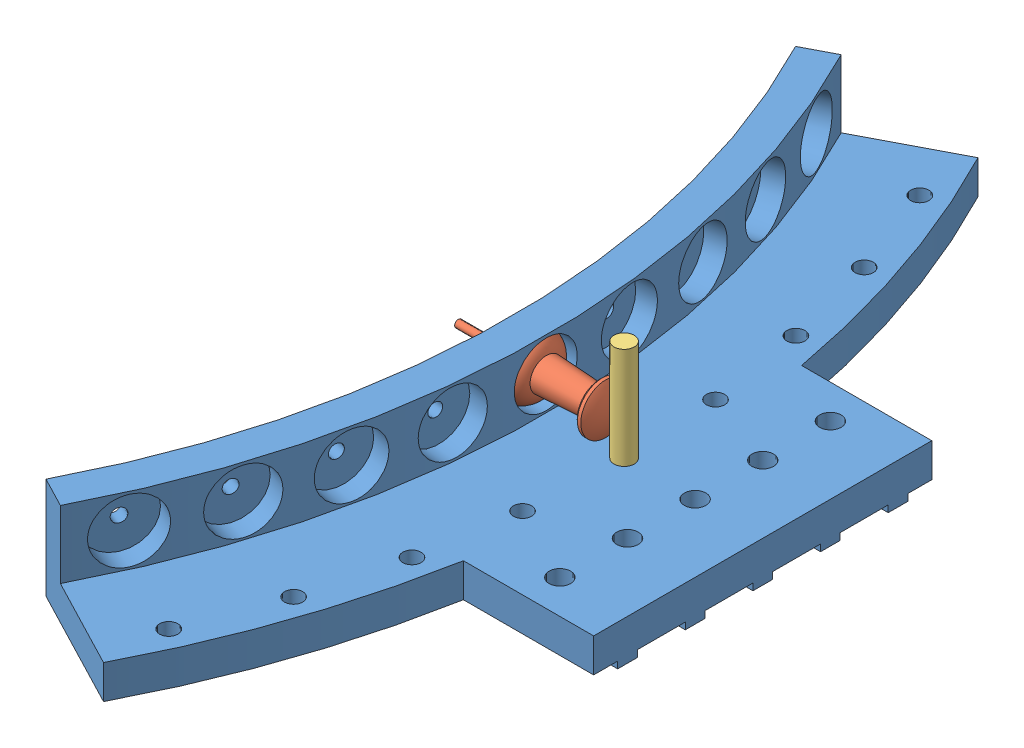
SolidWorks assembly ThumbtackWithSupport, configuration Default. Lengths in mm.
Overall size (50.56 21 129.29).
3 component instances, 3 part files, 4 mates.
Components (placement in the parent):
- ThumbtackSupport-1: ThumbtackSupport [Default] at (-94.9939 63.0635 100.913) size (50.56 16 129.29)
- Thumbtack-1: Thumbtack [Default] at (27.0061 73.0635 100.913) x (0 0 -1) z (1 0 0) size (9.3 9.3 22.8)
- Screw3mm-1: Screw3mm [Default] at (41.5061 83.0635 100.913) x (1 0 0) z (0 -1 0) size (3 3 20)
Mates (geometry in assembly coordinates):
- Coincident1: coincident anti-aligned: plane of ThumbtackSupport-1 through (27.0061 73.0635 100.913) normal (1 0 0); plane of Thumbtack-1 through (27.0061 73.6135 100.913) normal (-1 0 0)
- Coincident2: coincident aligned: cylinder of ThumbtackSupport-1 through (62.0071 73.0635 100.913) axis (-1 0 0) radius 4.65; circle of Thumbtack-1
- Concentric1: concentric anti-aligned: cylinder of ThumbtackSupport-1 through (41.5061 78.0635 100.913) axis (0 -1 0) radius 1.35; cylinder of Screw3mm-1 through (41.5061 63.0635 100.913) axis (0 1 0) radius 1.5
- Coincident3: coincident aligned: plane of ThumbtackSupport-1 through (11.4474 63.0635 45.5032) normal (0 -1 0); plane of Screw3mm-1 through (41.5061 63.0635 100.913) normal (0 -1 0)
